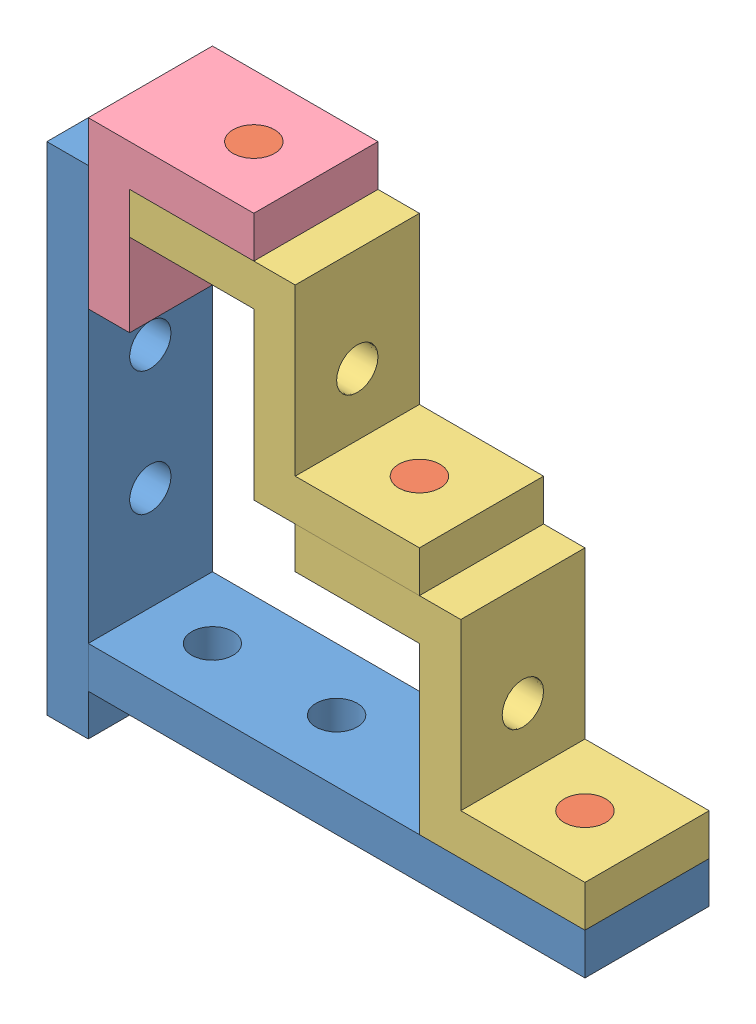
SolidWorks assembly HW7_WONG_P5-7, configuration Default. Lengths in mm.
Overall size (130 130 30).
9 component instances, 4 part files, 8 mates.
Components (placement in the parent):
- Plate_Quad-1: Plate_Quad [Default] at origin size (120 10 30)
- Peg_Short-1: Peg_Short [Default] at (105 0 -15) size (10 20 10)
- Peg_Short-2: Peg_Short [Default] at (10 95 -15) x (0 -1 0) z (0 0 -1) size (10 20 10)
- Peg_Short-3: Peg_Short [Default] at (25 100 -15) size (10 20 10)
- Peg_Short-4: Peg_Short [Default] at (65 50 -15) size (10 20 10)
- Plate_Quad-2: Plate_Quad [Default] at (0 -10 0) x (0 1 0) z (0 0 1) size (120 10 30)
- Z_Bracket-1: Z_Bracket [Default] at (80 60 -30) x (-1 0 0) z (0 0 -1) size (70 50 30)
- Z_Bracket-2: Z_Bracket [Default] at (120 10 -30) x (-1 0 0) z (0 0 -1) size (70 50 30)
- L_Bracket-1: L_Bracket [Default] at (0 110 -30) x (0 0 1) z (0 1 0) size (30 40 40)
Mates (geometry in assembly coordinates):
- Coincident1: coincident aligned: circle of Plate_Quad-1; circle of Peg_Short-1
- Coincident2: coincident aligned: circle of Peg_Short-1; circle of Z_Bracket-2
- Coincident3: coincident aligned: circle of Peg_Short-4; circle of Z_Bracket-2
- Coincident4: coincident aligned: circle of Peg_Short-4; circle of Z_Bracket-1
- Coincident5: coincident aligned: circle of Peg_Short-3; circle of Z_Bracket-1
- Coincident6: coincident aligned: circle of Peg_Short-3; circle of L_Bracket-1
- Coincident8: coincident anti-aligned: circle of Peg_Short-2; circle of L_Bracket-1
- Coincident9: coincident aligned: circle of Peg_Short-2; circle of Plate_Quad-2
